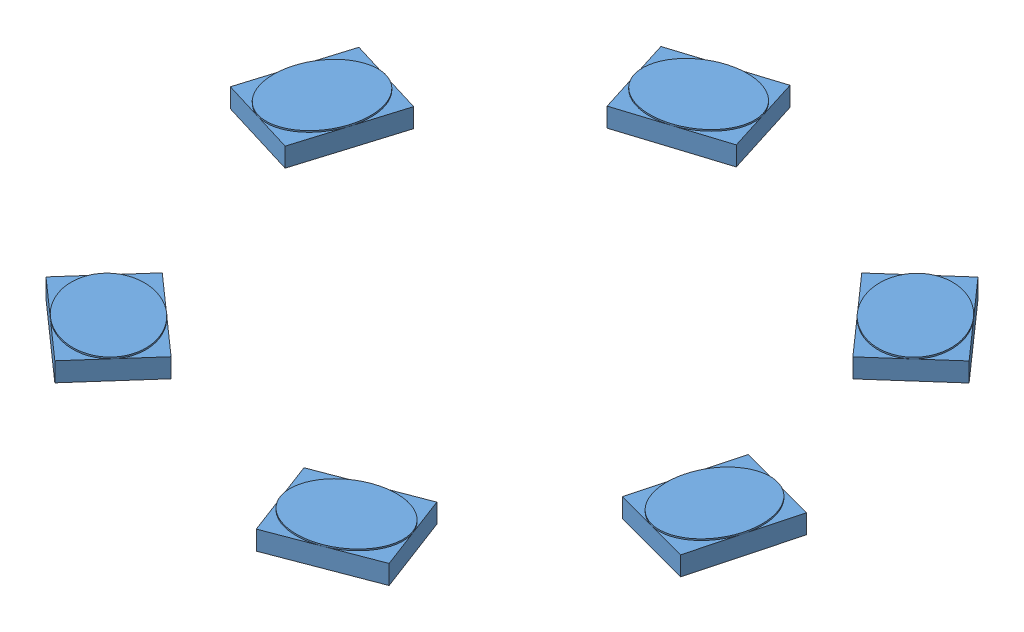
SolidWorks assembly led_pcb_assembly, configuration Default. Lengths in mm.
Overall size (23 5 25.5).
7 component instances, 2 part files, 19 mates.
Components (placement in the parent):
- pcb-1: pcb [Default] at origin size (23 5 25.5)
- led-1: led [Default] at (5.071 2 -6.8216) x (0.662524 0 0.749041) z (-0.749041 0 0.662524) size (3.5 0.7 2.8)
- led-2: led [Default] at (2.3197 2 11.0131) x (0.934581 0 -0.35575) z (0.35575 0 0.934581) size (3.5 0.7 2.8)
- led-3: led [Default] at (8.4879 2 0.4525) x (-0.25768 0 0.96623) z (-0.96623 0 -0.25768) size (3.5 0.7 2.8)
- led-4: led [Default] at (-10.1232 2 -4.9184) x (-0.291837 0 0.956468) z (-0.956468 0 -0.291837) size (3.5 0.7 2.8)
- led-5: led [Default] at (-4.1707 2 -7.4064) x (0.953699 0 -0.300763) z (0.300763 0 0.953699) size (3.5 0.7 2.8)
- led-6: led [Default] at (-8.6811 2 7.163) x (0.748631 0 0.662987) z (-0.662987 0 0.748631) size (3.5 0.7 2.8)
Mates (geometry in assembly coordinates):
- Coincident1: coordinate: point of pcb_v2-1
- Coincident4: coincident: circle of pcb_v2-1; point of led-4
- Coincident5: coincident: circle of pcb_v2-1; point of led-6
- Coincident6: coincident: circle of pcb_v2-1; point of led-3
- Coincident7: coincident: circle of pcb_v2-1; point of led-1
- Coincident8: coincident anti-aligned: plane of pcb_v2-1 through (0 2 0) normal (0 1 0); plane of led-4 through (-10.1232 2 -4.9184) normal (0 -1 0)
- Coincident9: coincident anti-aligned: plane of pcb_v2-1 through (0 2 0) normal (0 1 0); plane of led-6 through (-8.6811 2 7.163) normal (0 -1 0)
- Coincident10: coincident anti-aligned: plane of pcb_v2-1 through (0 2 0) normal (0 1 0); plane of led-3 through (8.4879 2 0.4525) normal (0 -1 0)
- Coincident11: coincident anti-aligned: plane of pcb_v2-1 through (0 2 0) normal (0 1 0); plane of led-1 through (5.071 2 -6.8216) normal (0 -1 0)
- Coincident12: coincident: circle of pcb_v2-1; point of led-2
- Coincident13: coincident: circle of pcb_v2-1; point of led-5
- Coincident14: coincident anti-aligned: plane of pcb_v2-1 through (0 2 0) normal (0 1 0); plane of led-2 through (2.3197 2 11.0131) normal (0 -1 0)
- Coincident15: coincident anti-aligned: plane of pcb_v2-1 through (0 2 0) normal (0 1 0); plane of led-5 through (-4.1707 2 -7.4064) normal (0 -1 0)
- Coincident16: coincident: circle of pcb_v2-1; point of led-6
- Coincident17: coincident: circle of pcb_v2-1; point of led-2
- Coincident18: coincident: circle of pcb_v2-1; point of led-3
- Coincident19: coincident: circle of pcb_v2-1; point of led-1
- Coincident20: coincident: circle of pcb_v2-1; point of led-5
- Coincident21: coincident: circle of pcb_v2-1; point of led-4
